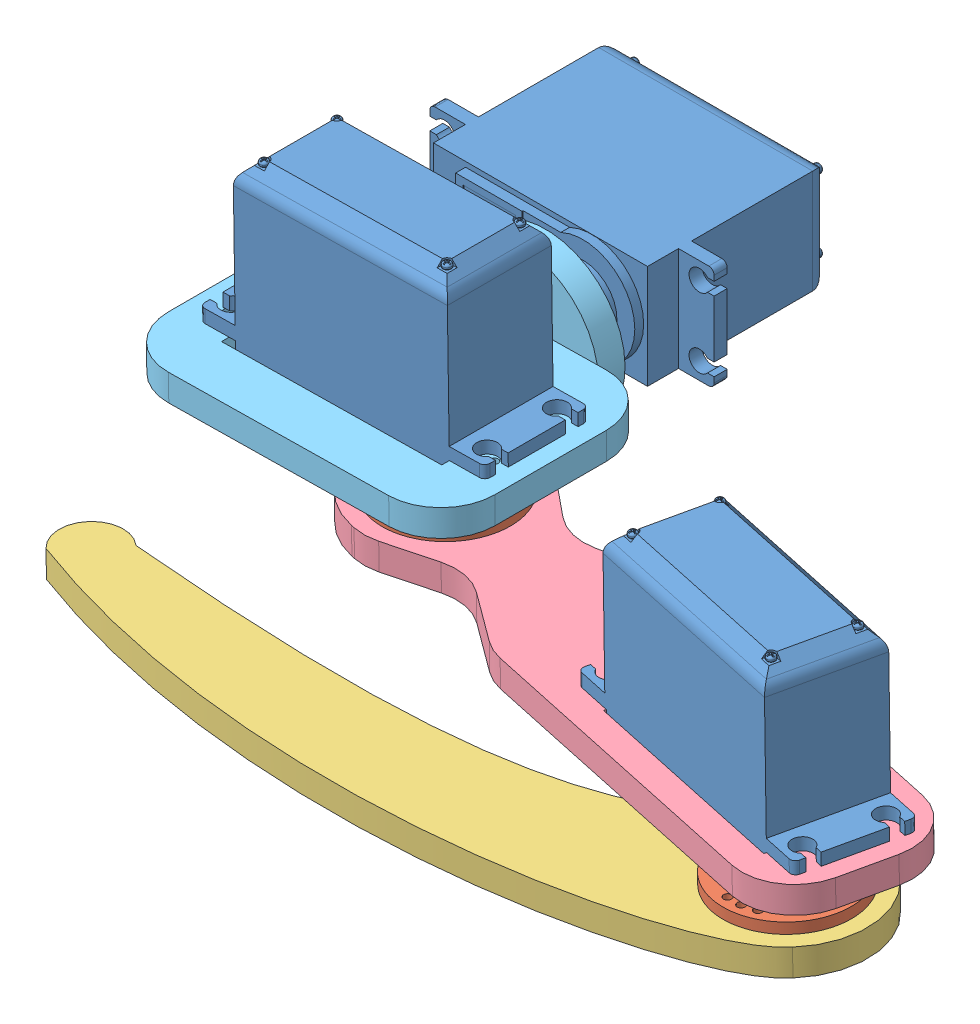
SolidWorks assembly left_leg, configuration Default. Lengths in mm.
Overall size (153.85 64.82 168.04).
9 component instances, 5 part files, 18 mates.
Components (placement in the parent):
- Standard Servo-1: Standard Servo [Default] at (7.4962 37.9612 45.4233) x (0.975235 0.014371 0.220702) z (0.220678 0.003252 -0.975341) size (53.74 42.63 19.57)
- Horn-1: Horn [Default] at (18.6873 -5.9787 49.4434) x (-0.992835 -0.01463 0.118593) z (0.118581 0.001747 0.992943) size (24 5 24)
- leg_3-1: leg_3 [Default] at (18.6873 -5.9787 49.4434) x (0.676034 0.009962 -0.736803) z (0.014734 -0.999891 0) size (110.29 105.51 5)
- leg_2-1: leg_2 [Default] at (-55.7402 2.6644 17.5168) x (-0.975235 -0.014371 -0.220702) z (-0.014734 0.999891 0) size (120 30 5)
- Standard Servo-2: Standard Servo [Default] at (-75.8092 51.474 29.4081) x (0.999891 0.014734 0) z (0 0 -1) size (53.74 42.63 19.57)
- Horn-2: Horn [Default] at (-63.991 7.5433 31.0024) x (-0.986182 -0.014532 0.165026) z (0.165009 0.002432 0.986289) size (24 5 24)
- leg_1-1: leg_1 [Default] at (-43.4589 5.0843 6.2174) x (0.999891 0.014734 0) z (0 0 1) size (61.5 30 46)
- Standard Servo-3: Standard Servo [Default] at (-81.3467 18.098 -37.8826) x (1 0 0) z (0 -1 0) size (53.74 42.63 19.57)
- Horn-3: Horn [Default] at (-70.177 19.6922 6.2174) x (1 0 0) z (0 -1 0) size (24 5 24)
Mates (geometry in assembly coordinates):
- Concentric3: concentric: cylinder of assembly; cylinder of assembly; cylinder of Standard Servo-1 through (18.562 2.5204 49.4434) axis (0.014734 -0.999891 0) radius 1.27; cylinder of Horn-1 through (18.6652 -4.4788 49.4434) axis (-0.014734 0.999891 0) radius 3
- Coincident2: coincident: plane of assembly; plane of assembly; plane of Standard Servo-1 through (18.6652 -4.4788 49.4434) normal (0.014734 -0.999891 0); plane of Horn-1 through (18.6652 -4.4788 49.4434) normal (-0.014734 0.999891 0)
- Concentric4: concentric: cylinder of assembly; cylinder of assembly; cylinder of Horn-1 through (18.6799 -5.4787 49.4434) axis (0.014734 -0.999891 0) radius 3; cylinder of leg_3-1 through (18.6873 -5.9787 49.4434) axis (0.014734 -0.999891 0) radius 3.25
- Coincident3: coincident: plane of assembly; plane of assembly; plane of Horn-1 through (30.6013 -5.8031 48.0203) normal (0.014734 -0.999891 0); plane of leg_3-1 through (-19.6553 -6.5437 74.077) normal (-0.014734 0.999891 0)
- Coincident4: coincident: plane of assembly; plane of assembly; plane of Standard Servo-1 through (26.633 2.8694 61.3031) normal (0.975235 0.014371 0.220702); plane of leg_2-1 through (26.4496 8.8761 61.7225) normal (-0.975235 -0.014371 -0.220702)
- Coincident6: coincident: plane of assembly; plane of assembly; plane of Standard Servo-1 through (-8.3698 2.3536 33.3169) normal (0.220678 0.003252 -0.975341); plane of leg_2-1 through (30.8632 8.9411 42.2156) normal (-0.220678 -0.003252 0.975341)
- Coincident8: coincident: plane of assembly; plane of assembly; plane of Standard Servo-1 through (-19.3208 8.2016 50.9235) normal (0.014734 -0.999891 0); plane of leg_2-1 through (-63.991 7.5433 31.0024) normal (-0.014734 0.999891 0)
- Coincident9: coincident: plane of assembly; plane of assembly; plane of Standard Servo-2 through (-64.0131 9.0432 31.0024) normal (0.014734 -0.999891 0); plane of Horn-2 through (-64.0131 9.0432 31.0024) normal (-0.014734 0.999891 0)
- Concentric5: concentric: cylinder of assembly; cylinder of assembly; cylinder of Standard Servo-2 through (-64.1162 16.0424 31.0024) axis (0.014734 -0.999891 0) radius 1.27; cylinder of Horn-2 through (-63.991 7.5433 31.0024) axis (0.014734 -0.999891 0) radius 1.4
- Concentric6: concentric: cylinder of assembly; cylinder of assembly; cylinder of leg_2-1 through (-63.991 7.5433 31.0024) axis (0.014734 -0.999891 0) radius 2.5; cylinder of Horn-2 through (-63.9983 8.0433 31.0024) axis (0.014734 -0.999891 0) radius 3
- Coincident10: coincident: plane of assembly; plane of assembly; plane of leg_2-1 through (-63.991 7.5433 31.0024) normal (-0.014734 0.999891 0); plane of Horn-2 through (-52.1568 7.7177 29.0221) normal (0.014734 -0.999891 0)
- Concentric7: concentric: cylinder of assembly; cylinder of assembly; cylinder of Standard Servo-3 through (-70.177 19.6922 -2.2826) axis (0 0 1) radius 1.27; cylinder of Horn-3 through (-70.177 19.6922 4.7174) axis (0 0 -1) radius 3
- Coincident14: coincident: plane of assembly; plane of assembly; plane of Standard Servo-3 through (-70.177 19.6922 4.7174) normal (0 0 1); plane of Horn-3 through (-70.177 19.6922 4.7174) normal (0 0 -1)
- Concentric8: concentric: cylinder of assembly; cylinder of assembly; cylinder of leg_1-1 through (-70.177 19.6922 10.2174) axis (0 0 -1) radius 3.25; cylinder of Horn-3 through (-70.177 19.6922 5.7174) axis (0 0 1) radius 3
- Coincident15: coincident: plane of assembly; plane of assembly; plane of leg_1-1 through (-43.4589 5.0843 6.2174) normal (0 0 -1); plane of Horn-3 through (-82.177 19.6922 6.2174) normal (0 0 1)
- Coincident18: coincident: plane of assembly; plane of assembly; plane of Standard Servo-2 through (-100.7406 21.7421 40.7874) normal (0.014734 -0.999891 0); plane of leg_1-1 through (-105.2101 21.6763 52.2174) normal (-0.014734 0.999891 0)
- Coincident19: coincident: plane of assembly; plane of assembly; plane of Standard Servo-2 through (-93.9428 15.8329 21.2174) normal (0 0 -1); plane of leg_1-1 through (-95.2112 21.8236 21.2174) normal (0 0 1)
- Coincident20: coincident: plane of assembly; plane of assembly; plane of Standard Servo-2 through (-53.6271 16.427 40.7874) normal (0.999891 0.014734 0); plane of leg_1-1 through (-53.7157 22.4351 42.2174) normal (-0.999891 -0.014734 0)
